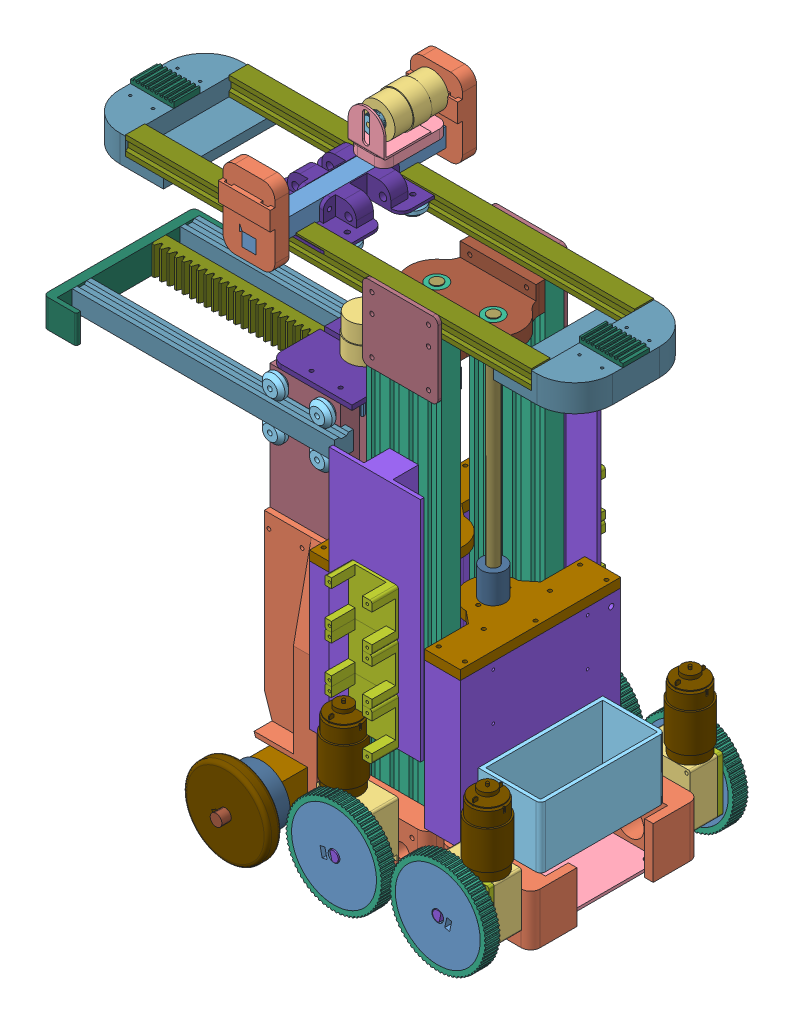
SolidWorks assembly Assem1, configuration Default. Lengths in mm.
Overall size (540.31 628.27 308).
103 component instances, 45 part files, 111 mates.
Components (placement in the parent):
- Part100-1: Part100 [Default] at (60.1378 -196.0708 30.4505) x (0.977925 -0.208957 0) z (0 0 1) size (90 90 15)
- Part101-1: Part101 [Default] at (49.6412 -183.4081 -4.0495) x (1 0 0) z (0 0 -1) size (98 54 49)
- Part102-1: Part102 [Default] at (-15.6307 -180.8424 -4.0495) size (58 58 29)
- Part103-1: Part103 [Default] at (-28.9187 -224.8424 -98.0495) x (-1 0 0) z (0 -1 0) size (70.08 132 3)
- Part104-1: Part104 [Default] at (-22.9227 -105.8424 -93.5094) x (-1 0 0) z (0 -1 0) size (66.08 132 65)
- Part105-1: Part105 [Default] at (-135.8811 -218.5126 -38.7594) x (1 0 0) z (0 1 0) size (80 20 485.87)
- Part106-1: Part106 [Default] at (-135.8811 -76.5831 2.2406) size (50 50 28)
- Part107-1: Part107 [Default] at (-74.9647 -16.3424 -93.5094) x (1 0 0) z (0 -1 0) size (38 170 154.5)
- Part108-1: Part108 [Default] at (-94.9648 -6.3424 -93.5094) x (-1 0 0) z (0 -1 0) size (78 170 10)
- Part109-1: Part109 [Default] at (-105.9648 23.6576 -93.5097) x (0.896428 0 -0.443189) z (0 -1 0) size (25 25 30)
- Part110-1: Part110 [Default] at (-135.8811 237.3574 -93.5094) x (1 0 0) z (0 1 0) size (118.94 89.5 30)
- Part111-1: Part111 [Default] at (-105.9648 -67.8424 -93.5097) x (0.95036 0 0.311152) z (-0.311152 0 0.95036) size (12 321 12)
- Part112-1: Part112 [Default] at (-135.8811 247.3573 -24.7594) x (-1 0 0) z (0 0 -1) size (80 80 4)
- Part113-1: Part113 [Default] at (2.1147 257.3574 -93.7594) x (1 0 0) z (0 1 0) size (86.08 130 28.45)
- Part114-1: Part114 [Default] at (22.1567 288.8074 -107.7594) x (-1 0 0) z (0 0 1) size (46 6 28)
- Part115-1: Part115 [Default] at (-0.9273 277.3573 -38.7594) x (0 -1 0) z (-1 0 0) size (20 20 430)
- Part116-1: Part116 [Default] at (-260.7818 282.6073 -93.2594) x (0 1 0) z (-1 0 0) size (23 130 95)
- Part117-1: Part117 [Default] at (-4.6307 -151.8424 13.9505) x (1 0 0) z (0 1 0) size (39.52 39.52 79)
- Part118-1: Part118 [Default] at (-275.8156 172.4073 -198.9094) x (0 -1 0) z (0 0 1) size (20 20 209.8)
- Part119-1: Part119 [Default] at (-233.1156 316.5315 5.8906) x (0 -1 0) z (-1 0 0) size (82.8 20 55)
- Part120-1: Part120 [Default] at (-105.9648 -224.8424 -93.5097) x (-0.837169 0 -0.546944) z (0 1 0) size (52 52 157)
- Part121-1: Part121 [Default] at (-241.6156 335.6073 -138.2594) x (0 1 0) z (-1 0 0) size (40 50 38)
- Part96-1: Part96 [Default] at (-225.7818 270.6073 -58.5094) x (0.753669 0 -0.657254) z (0 1 0) size (24 24 12)
- Part92-1: Part92 [Default] at (-25.8807 -190.3424 30.4505) size (102 101.94 15)
- Part179-1: Part179 [Default] at (-15.6307 -180.8424 24.9505) size (58 58 5.5)
- Part96-2: Part96 [Default] at (-225.7818 270.6073 -128.0094) x (1 0 0) z (0 1 0) size (24 24 12)
- Part96-3: Part96 [Default] at (-295.7818 270.6073 -58.5094) x (0.344788 0 0.93868) z (0 1 0) size (24 24 12)
- Part96-4: Part96 [Default] at (-295.7818 270.6073 -128.0094) x (0.999985 0 0.005483) z (0 1 0) size (24 24 12)
- Part257-1: Part257 [Default] at (-135.8811 -101.5831 -13.2594) x (1 0 0) z (0 1 0) size (96.66 31 241)
- Part106-2: Part106 [Default] at (-135.8811 -26.5831 2.2406) size (50 50 28)
- Part106-3: Part106 [Default] at (-135.8811 23.4169 2.2406) size (50 50 28)
- Part102-2: Part102 [Default] at (-15.6307 -180.8424 -211.9693) size (58 58 29)
- Part179-2: Part179 [Default] at (-15.6307 -180.8424 -217.4693) size (58 58 5.5)
- Part100-2: Part100 [Default] at (60.1378 -196.0708 -232.4693) x (0.977925 -0.208957 0) z (0 0 1) size (90 90 15)
- Part101-2: Part101 [Default] at (49.6412 -212.2766 -182.9693) size (98 54 49)
- Part117-2: Part117 [Default] at (-4.6307 -151.8424 -200.9693) x (1 0 0) z (0 1 0) size (39.52 39.52 79)
- Part92-2: Part92 [Default] at (-25.8807 -190.3424 -232.4693) size (102 101.94 15)
- Part105-2: Part105 [Default] at (-135.8811 267.3574 -148.2594) x (1 0 0) z (0 -1 0) size (80 20 485.87)
- Part112-2: Part112 [Default] at (-135.8811 247.3573 -158.2594) x (-1 0 0) z (0 0 -1) size (80 80 4)
- Part119-2: Part119 [Default] at (-233.1156 316.5315 -192.9094) x (0 -1 0) z (-1 0 0) size (82.8 20 55)
- Part257-2: Part257 [Default] at (-135.8811 139.4169 -173.7594) x (1 0 0) z (0 -1 0) size (96.66 31 241)
- Part106-4: Part106 [Default] at (-135.8811 -76.5831 -189.2594) x (1 0 0) z (0 0 -1) size (50 50 28)
- Part106-5: Part106 [Default] at (-135.8811 -26.5831 -189.2594) x (1 0 0) z (0 0 -1) size (50 50 28)
- Part106-6: Part106 [Default] at (-135.8811 23.4169 -189.2594) x (1 0 0) z (0 0 -1) size (50 50 28)
- Part115-2: Part115 [Default] at (-430.9273 277.3573 -148.2594) x (0 -1 0) z (1 0 0) size (20 20 430)
- Part111-2: Part111 [Default] at (-165.7974 -67.8424 -93.5097) x (-0.95036 0 0.311152) z (-0.311152 0 -0.95036) size (12 321 12)
- Part109-2: Part109 [Default] at (-165.7974 -6.3424 -93.5097) x (-0.896428 0 -0.443189) z (0 1 0) size (25 25 30)
- Part120-2: Part120 [Default] at (-165.7974 -224.8424 -93.5097) x (-0.837169 0 0.546944) z (0 1 0) size (52 52 157)
- Part107-2: Part107 [Default] at (-196.7974 13.6576 -93.51) x (-1 0 0) z (0 -1 0) size (38 170 154.5)
- Part108-2: Part108 [Default] at (-176.7974 23.6576 -93.51) x (1 0 0) z (0 -1 0) size (78 170 10)
- Part101-3: Part101 [Default] at (-211.4027 -183.4081 -182.9693) x (-1 0 0) z (0 0 1) size (98 54 49)
- Part100-3: Part100 [Default] at (-221.8992 -196.0708 -217.4693) x (-0.977925 -0.208957 0) z (0 0 -1) size (90 90 15)
- Part102-3: Part102 [Default] at (-146.1307 -180.8424 -182.9693) x (-1 0 0) z (0 0 -1) size (58 58 29)
- Part92-3: Part92 [Default] at (-135.8807 -190.3424 -217.4693) x (-1 0 0) z (0 0 -1) size (102 101.94 15)
- Part117-3: Part117 [Default] at (-157.1307 -151.8424 -200.9693) x (-1 0 0) z (0 1 0) size (39.52 39.52 79)
- Part100-4: Part100 [Default] at (-221.8992 -196.0708 45.4505) x (-0.977925 -0.208957 0) z (0 0 -1) size (90 90 15)
- Part102-4: Part102 [Default] at (-146.1307 -180.8424 24.9505) x (-1 0 0) z (0 0 -1) size (58 58 29)
- Part117-4: Part117 [Default] at (-157.1307 -151.8424 13.9505) x (-1 0 0) z (0 1 0) size (39.52 39.52 79)
- Part101-4: Part101 [Default] at (-211.4027 -212.2766 -4.0495) x (-1 0 0) z (0 0 -1) size (98 54 49)
- Part92-4: Part92 [Default] at (-135.8807 -190.3424 45.4505) x (-1 0 0) z (0 0 -1) size (102 101.94 15)
- assembly-1: assembly [Default] at (-532.5256 141.2373 -190.6107) x (-1 0 0) z (0 0 -1) size (311.13 413.02 300.82) (flexible)
  - backSlider.stp-1-solid27-1: backSlider.stp-1-solid27 [Default] at (-286.5622 -346.0796 -57.1007) x (-1 0 0) z (0 0 1) size (40 40 65)
  - Part87-1: Part87 [Default] at (-286.5622 -346.0796 7.8993) x (-0.760275 0.649602 0) z (0 0 1) size (60 60 24)
  - Part89-1: Part89 [Default] at (-286.5622 -346.0796 -68.1007) x (-0.760275 0.649602 0) z (0 0 1) size (12.4 12.4 125)
  - Part90-1: Part90 [Default] at (-279.2282 -164 -97.1007) x (1 0 0) z (0 -1 0) size (75 104 5)
  - Part91-1: Part91 [Default] at (-279.2282 -82 -65.1007) size (75 164 20)
  - Part93-1: Part93 [Default] at (-325.3773 -31.25 -39.8507) x (0 -1 0) z (1 0 0) size (20 20 278)
  - Part94-1: Part94 [Default] at (-54.8773 -21.25 -105.1005) x (-1 0 0) z (0 -1 0) size (35 160 30)
  - Part95-1: Part95 [Default] at (-167.3773 -36.25 -72.9132) x (-1 0 0) z (0 -1 0) size (240 15.62 54)
  - Part96-1: Part96 [Default] at (-303.6445 -11.5 -45.1007) x (0.999988 -0.004867 0) z (0 0 1) size (24 24 12)
  - Part97-1: Part97 [Default] at (-285.2282 5 -97.1007) x (1 0 0) z (0 -1 0) size (87 104 20)
  - wheel front without gear-2: wheel front without gear [Default] at (-813.0302 196.9967 26.563)
  - wheel with grat-1: wheel with grat [Default] at (-286.5622 -346.0796 39.3993) x (0.850516 -0.525949 0) z (0 0 1) size (90 90 15)
  - Part96-2: Part96 [Default] at (-253.6445 -11.5 -33.1007) x (-0.928778 -0.370636 0) z (0 0 -1) size (24 24 12)
  - Part96-3: Part96 [Default] at (-253.6445 -52 -45.1007) x (0.988499 0.151229 0) z (0 0 1) size (24 24 12)
  - Part96-4: Part96 [Default] at (-303.6445 -52 -45.1007) x (0.982944 0.183903 0) z (0 0 1) size (24 24 12)
  - Part98-1: Part98 [Default] at (-287.2282 -40.0491 -93.6007) x (1 0 0) z (0 1 0) size (40 39.32 20)
  - Part99-1: Part99 [Default] at (-279.2282 -249.1667 -45.1007) x (-1 0 0) z (0 0 1) size (75 234.33 25)
  - Part91-3: Part91 [Default] at (-279.2282 -82 -149.1007) size (75 164 20)
  - Part96-9: Part96 [Default] at (-253.6445 -11.5 -149.1007) x (-0.928778 -0.370636 0) z (0 0 -1) size (24 24 12)
  - Part96-10: Part96 [Default] at (-303.6445 -11.5 -161.1007) x (0.999988 -0.004867 0) z (0 0 1) size (24 24 12)
  - Part96-11: Part96 [Default] at (-303.6445 -52 -161.1007) x (0.982944 0.183903 0) z (0 0 1) size (24 24 12)
  - Part93-3: Part93 [Default] at (-47.3773 -31.25 -154.3507) x (0 -1 0) z (-1 0 0) size (20 20 278)
  - Part99-4: Part99 [Default] at (-279.2282 -249.1667 -149.1007) x (1 0 0) z (0 0 -1) size (75 234.33 25)
  - backSlider.stp-1-solid27-4: backSlider.stp-1-solid27 [Default] at (-286.5622 -346.0796 -137.1007) x (-1 0 0) z (0 0 -1) size (40 40 65)
  - Part87-4: Part87 [Default] at (-286.5622 -346.0796 -226.1007) x (-0.760275 0.649602 0) z (0 0 1) size (60 60 24)
  - wheel with grat-4: wheel with grat [Default] at (-286.5622 -346.0796 -233.6007) x (0.850516 -0.525949 0) z (0 0 -1) size (90 90 15)
  - Part89-4: Part89 [Default] at (-286.5622 -346.0796 -251.1007) x (-0.760275 0.649602 0) z (0 0 1) size (12.4 12.4 125)
  - Part96-12: Part96 [Default] at (-253.6445 -52 -161.1007) x (0.988499 0.151229 0) z (0 0 1) size (24 24 12)
- Part113-2: Part113 [Default] at (-433.9693 257.3574 -93.7594) x (-1 0 0) z (0 1 0) size (86.08 130 28.45)
- Part114-2: Part114 [Default] at (-454.0113 288.8074 -79.7594) x (1 0 0) z (0 0 -1) size (46 6 28)
- Part412-1: Part412 [Default] at (-261.6156 336.6073 -146.0153) x (-0.387473 0.921881 0) z (0 0 -1) size (38 38 67)
- Part413-1: Part413 [Default] at (-279.6156 315.6073 -182.2594) x (0 0 1) z (0 -1 0) size (69 38 10)
- Part414-1: Part414 [Default] at (-261.6156 336.6073 -117.0153) x (-0.718335 -0.695697 0) z (0 0 -1) size (17 17 10)
- Part124-1: Part124 [Default] at (-165.7974 252.3574 -93.5097) x (0.958188 0 -0.286138) z (0 -1 0) size (21 21 9.91)
- Part124-2: Part124 [Default] at (-105.9648 252.3574 -93.5097) x (-0.519343 0 -0.854566) z (0 -1 0) size (21 21 9.91)
- Part412-2: Part412 [Default] at (-245.2974 146.3126 -97.01) x (0.984952 0 0.172831) z (0 1 0) size (38 38 67)
- Part125-1: Part125 [Default] at (-245.9634 -204.8424 -138.5258) x (0.897137 -0.441751 0) z (0 0 1) size (18 18 5)
- Part125-2: Part125 [Default] at (-245.9634 -204.8424 -53.762) x (0.958888 0.283785 0) z (0 0 1) size (18 18 5)
- Part126-1: Part126 [Default] at (-135.8807 -190.3424 -214.633) x (-0.041584 -0.999135 0) z (0 0 -1) size (10.57 10.57 20)
- Part126-2: Part126 [Default] at (-25.8807 -190.3424 -212.0436) x (-0.01817 0.999835 0) z (0 0 -1) size (10.57 10.57 20)
- Part126-3: Part126 [Default] at (-135.8807 -190.3424 26.2136) x (-0.2422 0.970226 0) z (0 0 1) size (10.57 10.57 20)
- Part126-4: Part126 [Default] at (-25.8807 -190.3424 25.6519) x (-0.210354 -0.977625 0) z (0 0 1) size (10.57 10.57 20)
Mates (geometry in assembly coordinates):
- Concentric1: concentric aligned: cylinder of Part100-1 through (-25.8807 -190.3424 45.4505) axis (0 0 -1) radius 45; cylinder of Part92-1 through (-25.8807 -190.3424 45.4505) axis (0 0 -1) radius 45
- Coincident1: coincident aligned: plane of Part100-1 through (60.1378 -196.0708 30.4505) normal (0 0 -1); plane of Part92-1 through (-25.8807 -190.3424 30.4505) normal (0 0 -1)
- Coincident2: coincident anti-aligned: plane of Part102-1 through (-15.6307 -180.8424 24.9505) normal (0 0 1); plane of Part179-1 through (-15.6307 -180.8424 24.9505) normal (0 0 -1)
- Coincident3: coincident aligned: plane of Part102-1 through (13.3693 -180.8424 24.9505) normal (1 0 0); plane of Part179-1 through (13.3693 -180.8424 30.4505) normal (1 0 0)
- Coincident4: coincident aligned: plane of Part102-1 through (-15.6307 -151.8424 24.9505) normal (0 1 0); plane of Part179-1 through (-15.6307 -151.8424 30.4505) normal (0 1 0)
- Concentric2: concentric aligned: cylinder of Part100-1 through (-25.8807 -190.3424 45.4505) axis (0 0 -1) radius 6.2; cylinder of Part179-1 through (-25.8807 -190.3424 30.4505) axis (0 0 -1) radius 12
- Coincident5: coincident anti-aligned: plane of Part100-1 through (60.1378 -196.0708 30.4505) normal (0 0 -1); plane of Part179-1 through (-15.6307 -180.8424 30.4505) normal (0 0 1)
- Coincident6: coincident anti-aligned: plane of Part101-1 through (49.6412 -183.4081 -4.0495) normal (0 0 1); plane of Part102-1 through (-15.6307 -180.8424 -4.0495) normal (0 0 -1)
- Concentric4: concentric anti-aligned: cylinder of Part100-1 through (-25.8807 -190.3424 45.4505) axis (0 0 -1) radius 6.2; cylinder of Part101-1 through (-25.8807 -190.3424 -53.0495) axis (0 0 1) radius 15
- Parallel1: parallel aligned: plane of Part101-1 through (49.6412 -170.8424 -53.0495) normal (0 1 0); plane of Part102-1 through (-15.6307 -151.8424 24.9505) normal (0 1 0)
- Coincident8: coincident anti-aligned: plane of Part102-1 through (-15.6307 -151.8424 24.9505) normal (0 1 0); plane of Part117-1 through (-4.6307 -151.8424 13.9505) normal (0 -1 0)
- Tangent1: tangent aligned: plane of Part102-1 through (-15.6307 -180.8424 -4.0495) normal (0 0 -1); cylinder of Part117-1 through (-4.6307 -86.8424 13.9505) axis (0 -1 0) radius 18
- Tangent2: tangent aligned: plane of Part102-1 through (13.3693 -180.8424 24.9505) normal (1 0 0); cylinder of Part117-1 through (-4.6307 -86.8424 13.9505) axis (0 -1 0) radius 18
- Parallel2: parallel aligned: plane of Part101-1 through (23.1193 -183.4081 -53.0495) normal (1 0 0); plane of Part103-1 through (6.1233 -227.8424 -159.0495) normal (1 0 0)
- Coincident10: coincident anti-aligned: plane of Part101-1 through (49.6412 -224.8424 -53.0495) normal (0 -1 0); plane of Part103-1 through (1.1233 -224.8424 -159.0495) normal (0 1 0)
- Parallel3: parallel anti-aligned: plane of Part101-1 through (49.6412 -183.4081 -4.0495) normal (0 0 1); plane of Part104-1 through (-55.9647 -170.8424 -159.5094) normal (0 0 -1)
- Coincident11: coincident anti-aligned: plane of Part101-1 through (49.6412 -170.8424 -53.0495) normal (0 1 0); plane of Part104-1 through (5.1193 -170.8424 -154.5094) normal (0 -1 0)
- Coincident12: coincident anti-aligned: plane of Part104-1 through (-55.9647 -170.8424 -27.5094) normal (-1 0 0); plane of Part107-1 through (-55.9647 -170.8424 -178.5094) normal (1 0 0)
- Parallel4: parallel anti-aligned: plane of Part104-1 through (5.1193 -170.8424 -154.5094) normal (0 -1 0); plane of Part107-1 through (-105.9648 -16.3424 -93.5091) normal (0 1 0)
- Width1: width aligned: plane of Part107-1 through (-55.9647 -170.8424 -8.5094) normal (0 0 1); plane of Part107-1 through (-93.9647 -170.8424 -178.5094) normal (0 0 -1); plane of Part104-1 through (5.1193 -170.8424 -27.5094) normal (0 0 1); plane of Part104-1 through (-55.9647 -170.8424 -159.5094) normal (0 0 -1)
- Coincident13: coincident anti-aligned: plane of Part101-1 through (49.6412 -170.8424 -53.0495) normal (0 1 0); plane of Part107-1 through (-105.9648 -170.8424 -93.5091) normal (0 -1 0)
- Parallel5: parallel aligned: plane of Part107-1 through (-93.9647 -170.8424 -178.5094) normal (0 0 -1); plane of Part108-1 through (-93.9647 -16.3424 -178.5094) normal (0 0 -1)
- Parallel6: parallel aligned: plane of Part107-1 through (-105.9648 -16.3424 -93.5091) normal (0 1 0); plane of Part108-1 through (-105.9648 -6.3424 -93.5097) normal (0 1 0)
- Coincident14: coincident aligned: plane of Part107-1 through (-93.9647 -170.8424 -178.5094) normal (0 0 -1); plane of Part108-1 through (-93.9647 -16.3424 -178.5094) normal (0 0 -1)
- Coincident15: coincident aligned: plane of Part107-1 through (-55.9647 -170.8424 -178.5094) normal (1 0 0); plane of Part108-1 through (-55.9647 -16.3424 -178.5094) normal (1 0 0)
- Coincident16: coincident anti-aligned: plane of Part107-1 through (-105.9648 -16.3424 -93.5091) normal (0 1 0); plane of Part108-1 through (-105.9648 -16.3424 -93.5097) normal (0 -1 0)
- Concentric9: concentric anti-aligned: cylinder of Part108-1 through (-105.9648 -16.3424 -93.5097) axis (0 1 0) radius 12.5; cylinder of Part111-1 through (-105.9648 253.1576 -93.5097) axis (0 -1 0) radius 6
- Concentric10: concentric aligned: cylinder of Part111-1 through (-105.9648 253.1576 -93.5097) axis (0 -1 0) radius 6; cylinder of Part120-1 through (-105.9648 -109.8424 -93.5097) axis (0 -1 0) radius 26
- Coincident17: coincident aligned: plane of Part101-1 through (49.6412 -224.8424 -53.0495) normal (0 -1 0); plane of Part120-1 through (-105.9648 -224.8424 -93.5097) normal (0 -1 0)
- Concentric11: concentric aligned: cylinder of Part110-1 through (-105.9648 252.3574 -93.5097) axis (0 -1 0) radius 10.5; cylinder of Part111-1 through (-105.9648 253.1576 -93.5097) axis (0 -1 0) radius 6
- Parallel7: parallel aligned: plane of Part107-1 through (-55.9647 -170.8424 -8.5094) normal (0 0 1); plane of Part110-1 through (-135.8811 267.3574 -48.7594) normal (0 0 1)
- Coincident20: coincident anti-aligned: plane of Part111-1 through (-105.9648 -67.8424 -93.5097) normal (0 -1 0); plane of Part120-1 through (-105.9648 -67.8424 -93.5097) normal (0 1 0)
- Coincident21: coincident anti-aligned: plane of Part105-1 through (-130.5527 267.3574 -48.7594) normal (0 0 -1); plane of Part110-1 through (-135.8811 267.3574 -48.7594) normal (0 0 1)
- Coincident22: coincident aligned: plane of Part105-1 through (-95.8811 267.3574 -28.7594) normal (1 0 0); plane of Part110-1 through (-95.8811 267.3574 -93.5094) normal (1 0 0)
- Coincident23: coincident aligned: plane of Part105-1 through (-135.8811 267.3574 -38.7594) normal (0 1 0); plane of Part110-1 through (-135.8811 267.3574 -93.5094) normal (0 1 0)
- Coincident24: coincident anti-aligned: plane of Part105-1 through (-121.2095 267.3574 -28.7594) normal (0 0 1); plane of Part112-1 through (-101.8811 213.3573 -28.7594) normal (0 0 -1)
- Coincident25: coincident aligned: plane of Part105-1 through (-95.8811 267.3574 -28.7594) normal (1 0 0); plane of Part112-1 through (-95.8811 281.3573 -28.7594) normal (1 0 0)
- Coincident26: coincident anti-aligned: plane of Part105-1 through (-135.8811 267.3574 -38.7594) normal (0 1 0); plane of Part115-1 through (-430.9273 267.3574 -48.7594) normal (0 -1 0)
- Parallel8: parallel anti-aligned: plane of Part105-1 through (-95.8811 267.3574 -28.7594) normal (1 0 0); plane of Part115-1 through (-430.9273 277.3573 -38.7594) normal (-1 0 0)
- Coincident27: coincident anti-aligned: plane of Part112-1 through (-101.8811 213.3573 -28.7594) normal (0 0 -1); plane of Part115-1 through (-430.9273 267.3574 -28.7594) normal (0 0 1)
- Parallel9: parallel aligned: plane of Part112-1 through (-101.8811 213.3573 -24.7594) normal (0 0 1); plane of Part113-1 through (2.1147 267.3574 -28.7594) normal (0 0 1)
- Coincident28: coincident anti-aligned: plane of Part113-1 through (2.1147 267.3574 -93.7594) normal (0 1 0); plane of Part115-1 through (-430.9273 267.3574 -48.7594) normal (0 -1 0)
- Coincident29: coincident aligned: plane of Part113-1 through (2.1147 267.3574 -28.7594) normal (0 0 1); plane of Part115-1 through (-430.9273 267.3574 -28.7594) normal (0 0 1)
- Coincident30: coincident anti-aligned: plane of Part113-1 through (-0.9273 285.8074 -93.7594) normal (-1 0 0); plane of Part115-1 through (-0.9273 277.3573 -38.7594) normal (1 0 0)
- Parallel10: parallel aligned: plane of Part113-1 through (2.1147 285.8074 -93.7594) normal (0 1 0); plane of Part116-1 through (-260.7818 285.6073 -93.2594) normal (0 1 0)
- Parallel11: parallel aligned: plane of Part113-1 through (45.1567 267.3574 -93.7594) normal (1 0 0); plane of Part116-1 through (-224.3656 305.6073 -93.2594) normal (1 0 0)
- Concentric12: concentric anti-aligned: circle of Part116-1; cylinder of Part96-1 through (-225.7818 282.6073 -58.5094) axis (0 -1 0) radius 2.5
- Coincident31: coincident anti-aligned: plane of Part116-1 through (-260.7818 282.6073 -93.2594) normal (0 -1 0); plane of Part96-1 through (-225.7818 282.6073 -58.5094) normal (0 1 0)
- Concentric17: concentric aligned: cylinder of Part116-1 through (-225.7818 285.6073 -128.0094) axis (0 -1 0) radius 2.5; cylinder of Part96-2 through (-225.7818 282.6073 -128.0094) axis (0 -1 0) radius 12
- Concentric18: concentric aligned: cylinder of Part116-1 through (-295.7818 285.6073 -128.0094) axis (0 -1 0) radius 2.5; cylinder of Part96-4 through (-295.7818 282.6073 -128.0094) axis (0 -1 0) radius 12
- Coincident33: coincident anti-aligned: plane of Part116-1 through (-260.7818 282.6073 -93.2594) normal (0 -1 0); plane of Part96-4 through (-295.7818 282.6073 -128.0094) normal (0 1 0)
- Coincident34: coincident anti-aligned: plane of Part116-1 through (-260.7818 282.6073 -93.2594) normal (0 -1 0); plane of Part96-2 through (-225.7818 282.6073 -128.0094) normal (0 1 0)
- Concentric19: concentric aligned: cylinder of Part116-1 through (-295.7818 285.6073 -58.5094) axis (0 -1 0) radius 2.5; cylinder of Part96-3 through (-295.7818 282.6073 -58.5094) axis (0 -1 0) radius 2.5
- Coincident35: coincident anti-aligned: plane of Part116-1 through (-260.7818 282.6073 -93.2594) normal (0 -1 0); plane of Part96-3 through (-295.7818 282.6073 -58.5094) normal (0 1 0)
- Tangent4: tangent anti-aligned: plane of Part115-1 through (-430.9273 274.6073 -46.5094) normal (0 0.707107 -0.707107); cone of Part96-1 through (-225.7818 274.6073 -58.5094) axis (0 -1 0)
- Tangent5: tangent anti-aligned: plane of Part115-1 through (-430.9273 280.1073 -46.5094) normal (0 0 -1); cylinder of Part96-1 through (-225.7818 282.6073 -58.5094) axis (0 -1 0) radius 12
- Coincident36: coincident anti-aligned: plane of Part116-1 through (-260.7818 285.6073 -93.2594) normal (0 1 0); plane of Part118-1 through (-250.6156 285.6073 10.8906) normal (0 -1 0)
- Coincident37: coincident anti-aligned: plane of Part116-1 through (-250.6156 305.6073 -93.2594) normal (-1 0 0); plane of Part118-1 through (-250.6156 305.6073 10.8906) normal (1 0 0)
- Width3: width anti-aligned: plane of Part118-1 through (-275.8156 172.4073 10.8906) normal (0 0 1); plane of Part118-1 through (-275.8156 172.4073 -198.9094) normal (0 0 -1); plane of Part116-1 through (-260.7818 305.6073 -121.2594) normal (0 0 -1); plane of Part116-1 through (-260.7818 305.6073 -66.7594) normal (0 0 1)
- Coincident38: coincident anti-aligned: plane of Part118-1 through (-250.6156 285.6073 10.8906) normal (0 -1 0); plane of Part119-1 through (-233.1156 285.6073 -44.1094) normal (0 1 0)
- Parallel13: parallel aligned: plane of Part118-1 through (-275.8156 172.4073 10.8906) normal (0 0 1); plane of Part119-1 through (-288.1156 345.4316 10.8906) normal (0 0 1)
- Width4: width anti-aligned: plane of Part118-1 through (-270.6156 305.6073 10.8906) normal (-1 0 0); plane of Part118-1 through (-250.6156 305.6073 10.8906) normal (1 0 0); plane of Part119-1 through (-267.8882 316.5315 -44.1094) normal (1 0 0); plane of Part119-1 through (-253.343 316.5315 -44.1094) normal (-1 0 0)
- Coincident39: coincident aligned: plane of Part118-1 through (-275.8156 172.4073 10.8906) normal (0 0 1); plane of Part119-1 through (-288.1156 345.4316 10.8906) normal (0 0 1)
- Width5: width aligned: plane of Part105-1 through (-95.8811 267.3574 -28.7594) normal (1 0 0); plane of Part105-1 through (-175.8811 267.3574 -48.7594) normal (-1 0 0); plane of Part257-1 through (-120.5527 139.4169 -1.7594) normal (1 0 0); plane of Part257-1 through (-151.2095 139.4169 -28.7594) normal (-1 0 0)
- Coincident40: coincident anti-aligned: plane of Part105-1 through (-141.2095 267.3574 -28.7594) normal (0 0 1); plane of Part257-1 through (-120.5527 139.4169 -28.7594) normal (0 0 -1)
- Coincident41: coincident aligned: plane of Part106-1 through (-135.8811 -101.5831 5.2406) normal (0 -1 0); plane of Part257-1 through (-135.8811 -101.5831 -13.2594) normal (0 -1 0)
- Coincident42: coincident anti-aligned: plane of Part106-1 through (-135.8811 -76.5831 2.2406) normal (0 0 -1); plane of Part257-1 through (-184.2095 139.4169 2.2406) normal (0 0 1)
- Width7: width aligned: plane of Part257-1 through (-184.2095 139.4169 -1.7594) normal (-1 0 0); plane of Part257-1 through (-87.5527 139.4169 2.2406) normal (1 0 0); plane of Part106-1 through (-160.8811 -76.5831 5.2406) normal (-1 0 0); plane of Part106-1 through (-110.8811 -76.5831 5.2406) normal (1 0 0)
- Coincident43: coincident anti-aligned: plane of Part113-1 through (2.1147 285.8074 -93.7594) normal (0 1 0); plane of Part114-1 through (-0.8433 285.8074 -79.7594) normal (0 -1 0)
- Width8: width aligned: plane of Part113-1 through (2.1147 267.3574 -158.7594) normal (0 0 -1); plane of Part113-1 through (2.1147 267.3574 -28.7594) normal (0 0 1); plane of Part114-1 through (22.1567 288.8074 -107.7594) normal (0 0 -1); plane of Part114-1 through (22.1567 288.8074 -79.7594) normal (0 0 1)
- Coincident44: coincident aligned: plane of Part113-1 through (45.1567 267.3574 -93.7594) normal (1 0 0); plane of Part114-1 through (45.1567 285.8074 -79.7594) normal (1 0 0)
- Concentric20: concentric anti-aligned: cylinder of Part109-1 through (-105.9648 -6.3424 -93.5097) axis (0 1 0) radius 12.5; cylinder of Part111-1 through (-105.9648 253.1576 -93.5097) axis (0 -1 0) radius 6
- Coincident45: coincident anti-aligned: plane of Part108-1 through (-105.9648 -6.3424 -93.5097) normal (0 1 0); plane of Part109-1 through (-105.9648 -6.3424 -93.5097) normal (0 -1 0)
- Coincident46: coincident aligned: plane of Part107-2 through (-215.7974 -140.8424 -178.51) normal (0 0 -1); plane of Part108-2 through (-215.7974 13.6576 -178.51) normal (0 0 -1)
- Coincident47: coincident aligned: plane of Part107-2 through (-215.7974 -140.8424 -8.51) normal (-1 0 0); plane of Part108-2 through (-215.7974 13.6576 -8.51) normal (-1 0 0)
- Coincident48: coincident anti-aligned: plane of Part107-2 through (-165.7974 13.6576 -93.5103) normal (0 1 0); plane of Part108-2 through (-165.7974 13.6576 -93.5097) normal (0 -1 0)
- Parallel14: parallel aligned: plane of Part105-1 through (-175.8811 267.3574 -48.7594) normal (-1 0 0); plane of Part107-2 through (-215.7974 -140.8424 -8.51) normal (-1 0 0)
- Concentric21: concentric anti-aligned: cylinder of Part111-2 through (-165.7974 253.1576 -93.5097) axis (0 -1 0) radius 6; cylinder of Part108-2 through (-165.7974 13.6576 -93.5097) axis (0 1 0) radius 12.5
- Parallel15: parallel aligned: plane of Part101-3 through (-184.8807 -183.4081 -133.9693) normal (-1 0 0); plane of assembly-1/Part99-1 through (-290.7974 -107.9294 -151.51) normal (-1 0 0)
- Parallel16: parallel aligned: plane of Part108-2 through (-165.7974 23.6576 -93.5097) normal (0 1 0); plane of assembly-1/Part97-1 through (-247.2974 146.2373 -93.51) normal (0 1 0)
- Coincident49: coincident aligned: plane of Part101-4 through (-211.4027 -224.8424 -53.0495) normal (0 -1 0); plane of assembly-1/backSlider.stp-1-solid27-1 through (-265.9634 -224.8424 -198.51) normal (0 -1 0)
- Coincident50: coincident anti-aligned: plane of Part107-2 through (-215.7974 -140.8424 -8.51) normal (-1 0 0); plane of assembly-1/Part91-3 through (-215.7974 141.2373 -61.51) normal (1 0 0)
- Width9: width aligned: plane of Part107-2 through (-177.7974 -140.8424 -8.51) normal (0 0 1); plane of Part107-2 through (-215.7974 -140.8424 -178.51) normal (0 0 -1); plane of assembly-1/Part91-3 through (-253.2974 59.2373 -41.51) normal (0 0 1); plane of assembly-1/Part91-1 through (-253.2974 59.2373 -145.51) normal (0 0 -1)
- Concentric22: concentric aligned: cylinder of Part412-1 through (-261.6156 336.6073 -117.0153) axis (0 0 -1) radius 2.5; cylinder of Part414-1 through (-261.6156 336.6073 -117.0153) axis (0 0 -1) radius 2.5
- Coincident51: coincident anti-aligned: plane of Part412-1 through (-261.6156 336.6073 -127.0153) normal (0 0 1); plane of Part414-1 through (-261.6156 336.6073 -127.0153) normal (0 0 -1)
- Coincident52: coincident anti-aligned: plane of Part118-1 through (-250.6156 305.6073 10.8906) normal (0 1 0); plane of Part413-1 through (-279.6156 305.6073 -182.2594) normal (0 -1 0)
- Width10: width anti-aligned: plane of Part413-1 through (-279.6156 305.6073 -182.2594) normal (-1 0 0); plane of Part413-1 through (-241.6156 305.6073 -182.2594) normal (1 0 0); plane of Part118-1 through (-250.6156 305.6073 10.8906) normal (1 0 0); plane of Part118-1 through (-270.6156 305.6073 10.8906) normal (-1 0 0)
- Coincident53: coincident anti-aligned: plane of Part121-1 through (-279.6156 315.6073 -138.2594) normal (0 -1 0); plane of Part413-1 through (-279.6156 315.6073 -182.2594) normal (0 1 0)
- Coincident54: coincident aligned: plane of Part121-1 through (-279.6156 335.6073 -113.2594) normal (0 0 1); plane of Part413-1 through (-279.6156 305.6073 -113.2594) normal (0 0 1)
- Width11: width aligned: plane of Part413-1 through (-279.6156 305.6073 -182.2594) normal (-1 0 0); plane of Part413-1 through (-241.6156 305.6073 -182.2594) normal (1 0 0); plane of Part121-1 through (-279.6156 335.6073 -138.2594) normal (-1 0 0); plane of Part121-1 through (-241.6156 335.6073 -138.2594) normal (1 0 0)
- Tangent7: tangent anti-aligned: plane of Part121-1 through (-279.6156 317.6073 -138.2594) normal (0 1 0); cylinder of Part412-1 through (-261.6156 336.6073 -165.0153) axis (0 0 1) radius 19
- Tangent9: tangent aligned: plane of Part121-1 through (-279.6156 335.6073 -138.2594) normal (-1 0 0); cylinder of Part412-1 through (-261.6156 336.6073 -127.0153) axis (0 0 -1) radius 18
- Coincident55: coincident aligned: plane of Part112-1 through (-169.8811 287.3573 -28.7594) normal (0 1 0); plane of Part115-1 through (-430.9273 287.3573 -28.7594) normal (0 1 0)
- Distance1: distance = 10 mm aligned: plane of Part413-1 through (-279.6156 305.6073 -113.2594) normal (0 0 1); plane of Part116-1 through (-260.7818 285.6073 -103.2594) normal (0 0 1)
- Coincident56: coincident anti-aligned: plane of Part105-1 through (-135.8811 267.3574 -38.7594) normal (0 1 0); plane of Part115-1 through (-430.9273 267.3574 -48.7594) normal (0 -1 0)
- Distance2: distance = 178.9198 mm anti-aligned: plane of Part101-1 through (49.6412 -183.4081 -4.0495) normal (0 0 1); plane of Part101-2 through (49.6412 -212.2766 -182.9693) normal (0 0 -1)
- Distance3: distance = 13 mm aligned: plane of Part104-1 through (10.1193 -170.8424 -154.5094) normal (1 0 0); plane of Part101-1 through (23.1193 -183.4081 -53.0495) normal (1 0 0)
- Coincident57: coincident anti-aligned: plane of Part110-1 through (-135.8811 267.3574 -93.5094) normal (0 1 0); plane of Part115-2 through (-0.9273 267.3574 -138.2594) normal (0 -1 0)
- Width12: width anti-aligned: plane of assembly-1/Part91-1 through (-253.2974 59.2373 -145.51) normal (0 0 -1); plane of assembly-1/Part91-3 through (-253.2974 59.2373 -41.51) normal (0 0 1); plane of assembly-1/Part97-1 through (-247.2974 141.2373 -41.51) normal (0 0 1); plane of assembly-1/Part97-1 through (-247.2974 141.2373 -145.51) normal (0 0 -1)
- Concentric23: concentric anti-aligned: circle of Part110-1; circle of Part124-1
- Concentric24: concentric anti-aligned: circle of Part124-2; circle of Part110-1
- Concentric25: concentric anti-aligned: circle of assembly-1/Part97-1; circle of Part412-2
- Concentric26: concentric anti-aligned: circle of assembly-1/backSlider.stp-1-solid27-1; circle of Part125-1
- Concentric27: concentric aligned: circle of assembly-1/backSlider.stp-1-solid27-4; circle of Part125-2
- Concentric29: concentric aligned: circle of Part100-3; circle of Part126-1
- Concentric30: concentric anti-aligned: circle of Part100-2; circle of Part126-2
- Concentric31: concentric anti-aligned: circle of Part100-4; circle of Part126-3
- Concentric32: concentric aligned: circle of Part100-1; circle of Part126-4
- Coincident66: coincident anti-aligned: circle of Part109-2; circle of Part108-2
- Coincident69: coincident aligned: circle of Part110-1; plane of Part124-2 through (-105.9648 252.3574 -93.5097) normal (0 1 0)
- Coincident71: coincident aligned: circle of Part110-1; plane of Part124-1 through (-165.7974 252.3574 -93.5097) normal (0 1 0)
